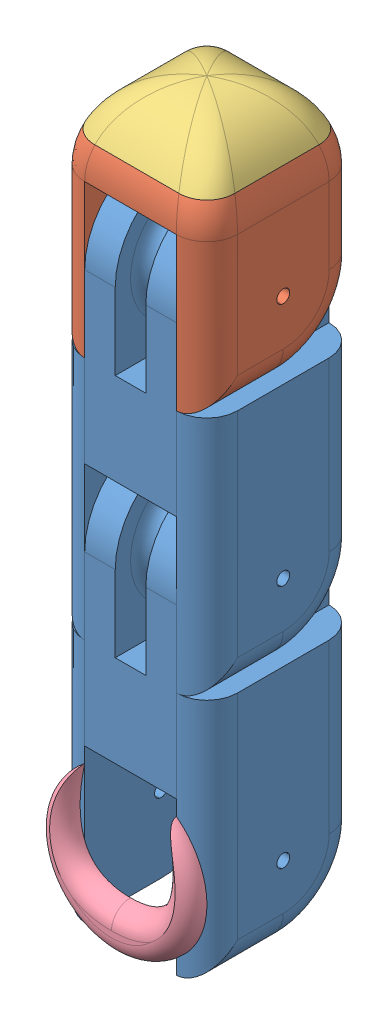
SolidWorks assembly Finger Assembly 3, configuration Default. Lengths in mm.
Overall size (20 94 23.03).
5 component instances, 4 part files, 13 mates.
Components (placement in the parent):
- Finger Body 3-1: Finger Body 3 [Default] at (8.0779 21.877 43.4324) size (20 52 20)
- Finger Body 3-2: Finger Body 3 [Default] at (8.0779 53.877 43.4324) size (20 52 20)
- Finger Top-1: Finger Top [Default] at (8.0779 85.877 43.4324) size (20 24 20)
- Finger Tip-1: Finger Tip [Default] at (8.0779 85.877 43.4324) size (18.77 6 18.77)
- Finger Moon-1: Finger Moon [Default] at (8.0779 11.877 53.4324) x (1 0 0) z (0 -1 0) size (20 3.57 18.53)
Mates (geometry in assembly coordinates):
- Coincident1: coincident anti-aligned: plane of Finger Body-1 through (14.0779 43.877 53.4324) normal (1 0 0); plane of Finger Body 3-2 through (14.0779 43.877 33.4324) normal (-1 0 0)
- LimitAngle1: limit planar angle = 1.570796 rad aligned: plane of Finger Body-2 through (-1.9221 65.877 53.4324) normal (0 0 1); plane of Finger Body-1 through (8.0779 33.877 43.4324) normal (0 1 0)
- Coincident2: coincident anti-aligned: plane of Finger Body 3-2 through (14.0779 75.877 53.4324) normal (1 0 0); plane of Finger Top-1 through (14.0779 75.877 53.4324) normal (-1 0 0)
- Concentric2: concentric aligned: circle of Finger Body-2; circle of Finger Top-1
- LimitAngle2: limit planar angle = 1.570796 rad anti-aligned: plane of Finger Top-1 through (18.0779 89.877 27.2077) normal (0 1 0); plane of Finger Body-2 through (-1.9221 65.877 53.4324) normal (0 0 1)
- Concentric3: concentric aligned: circle of Finger Body-1; circle of Finger Body-2
- Coincident5: coincident anti-aligned: plane of Finger Top-1 through (18.0779 89.877 27.2077) normal (0 1 0); plane of Finger Tip-1 through (-1.9221 89.877 53.958) normal (0 -1 0)
- Coincident6: coincident anti-aligned: line of Finger Top-1 through (2.5788 89.877 52.5976) axis (1 0 0); line of Finger Tip-1 through (13.577 89.877 52.5976) axis (-1 0 0)
- Coincident7: coincident anti-aligned: line of Finger Top-1 through (-1.0873 89.877 37.9334) axis (0 0 1); line of Finger Tip-1 through (-1.0873 89.877 48.9315) axis (0 0 -1)
- Coincident8: coincident anti-aligned: plane of Finger Body 3-1 through (-1.9221 33.877 53.4324) normal (0 0 1); plane of Finger Moon-1 through (2.2963 10.7209 53.4324) normal (0 0 -1)
- Coincident9: coincident: line of Finger Body 3-1 through (2.0779 1.877 53.4324) axis (0 1 0); point of Finger Moon-1
- Coincident10: coincident: line of Finger Body 3-1 through (14.0779 1.877 53.4324) axis (0 1 0); point of Finger Moon-1
- Coincident11: coincident aligned: line of Finger Body 3-1 through (14.0779 1.877 53.4324) axis (0 0 -1); line of Finger Moon-1 through (14.0779 1.877 53.4324) axis (0 0 -1)
